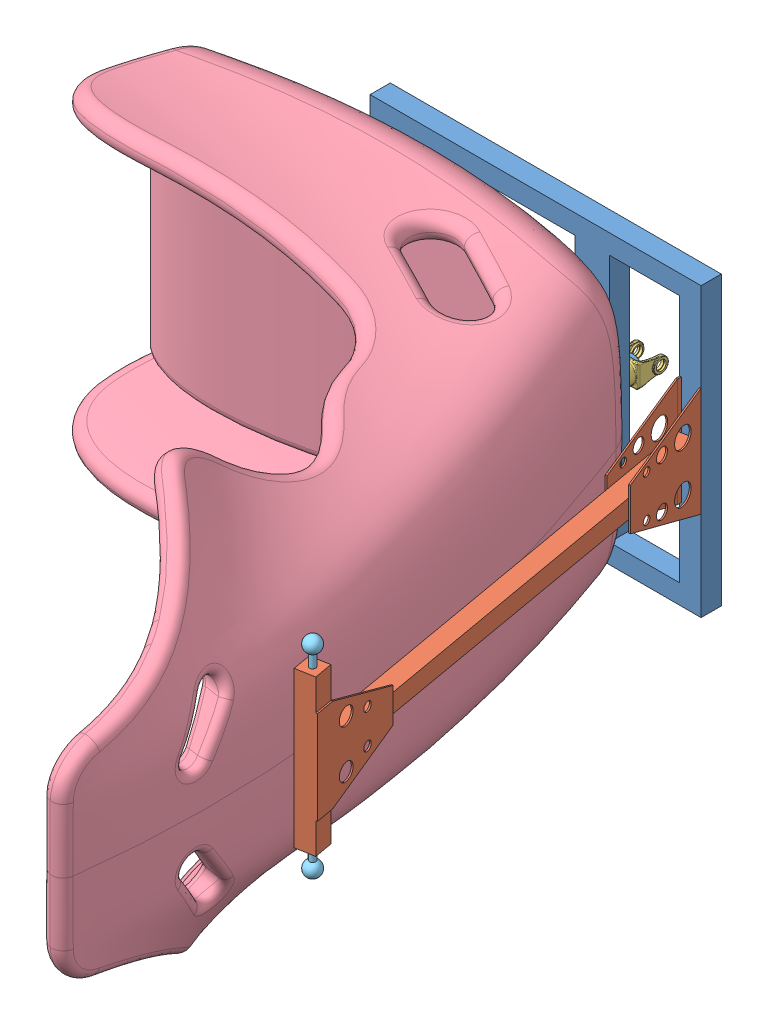
SolidWorks assembly siege, configuration Défaut. Lengths in mm.
Overall size (1024.11 731.48 1108.83).
6 component instances, 5 part files, 12 mates.
Components (placement in the parent):
- support_siege_inferieur-1: support_siege_inferieur [Défaut] at origin size (426 370 52)
- support_siege_arriere-1: support_siege_arriere [Défaut] at (424.1282 -171.5 26.7272) x (0.173648 0 0.984808) z (-0.984808 0 0.173648) size (636.1 200 32.48)
- fourche-1: fourche [Défaut] at (286 -160 22.15) x (0 1 0) z (-1 0 0) size (30.18 53.98 36.51)
- siege-1: siege [Défaut] at (-162.8445 -147.6332 -30.6502) x (-0.014699 -0.999786 -0.014541) z (-0.988338 0.016732 -0.151352) size (705.1 977.38 875.83)
- joint_rotule_male-1: joint_rotule_male [Défaut] at (515.8074 -284.5 615.7706) x (-0.898781 0 0.438397) z (0 1 0) size (20 20 35)
- joint_rotule_male-2: joint_rotule_male [Défaut] at (515.8074 -34.5 615.7706) x (0.795824 0 -0.605528) z (0 -1 0) size (20 20 35)
Mates (geometry in assembly coordinates):
- Coaxiale1: concentric aligned: cylinder of support_siege_inferieur-1; cylinder of fourche-1
- Coïncidente6: coincident anti-aligned: plane of support_siege_inferieur-1 through (0 25 0) normal (0 0 -1); plane of fourche-1 through (286 -160 0) normal (0 0 1)
- Parallèle1: parallel aligned: plane of support_siege_inferieur-1 through (264 0 26) normal (-1 0 0); plane of fourche-1 through (269.3313 -144.9188 -18.6246) normal (-1 0 0)
- Coïncidente8: coincident aligned: plane of support_siege_inferieur-1 through (426 0 26) normal (1 0 0); plane of support_siege_arriere-1 through (426 -89.5 26) normal (1 0 0)
- Coïncidente7: coincident: plane of support_siege_inferieur-1 through (0 25 26) normal (0 0 1); line of support_siege_arriere-1
- Distance1: distance = 172.5 mm aligned: plane of support_siege_inferieur-1 through (0 25 26) normal (0 1 0); plane of support_siege_arriere-1 through (400.4928 -147.5 30.8947) normal (0 1 0)
- Tangent3: tangent: plane of support_siege_inferieur-1 through (0 25 26) normal (0 0 1); face of siege-1
- Tangent5: tangent: plane of support_siege_arriere-1 through (501.9357 -259.5 606.2055) normal (-0.984808 0 0.173648); face of siege-1
- Coïncidente9: coincident anti-aligned: plane of support_siege_arriere-1 through (525.571 -259.5 602.038) normal (0 -1 0); plane of joint_rotule_male-1 through (515.8074 -259.5 615.7706) normal (0 1 0)
- Coaxiale2: concentric anti-aligned: cylinder of support_siege_arriere-1; cylinder of joint_rotule_male-1
- Coïncidente10: coincident anti-aligned: plane of support_siege_arriere-1 through (525.571 -59.5 602.038) normal (0 1 0); plane of joint_rotule_male-2 through (515.8074 -59.5 615.7706) normal (0 -1 0)
- Coaxiale3: concentric aligned: cylinder of support_siege_arriere-1; cylinder of joint_rotule_male-2
